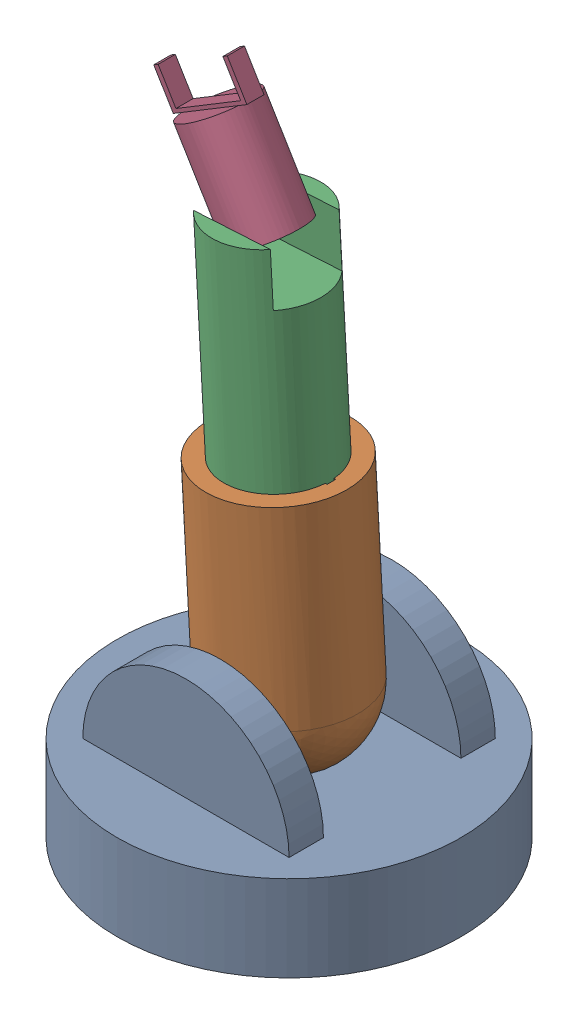
SolidWorks assembly Assem1, configuration Default. Lengths in mm.
Overall size (200 380.93 200).
4 component instances, 4 part files, 4 mates.
Components (placement in the parent):
- part1-1: part1 [Default] at (-37.4269 31.4025 224.8685) size (200 110 200)
- Part2-1: Part2 [Default] at (-37.4269 111.4025 224.8685) x (0.998352 0.057379 0) z (-0.057379 0.998352 0) size (80 100 150)
- Part3-1: Part3 [Default] at (-50.624 341.0236 224.8685) x (0 0 -1) z (0.057379 -0.998352 0) size (60 61 220)
- Part4-1: Part4 [Default] at (-48.3769 330.9431 224.8685) x (0.855727 0.517427 0) z (-0.517427 0.855727 0) size (50 50 80)
Mates (geometry in assembly coordinates):
- Coincident1: coincident anti-aligned: circle of part1-1; circle of Part2-1
- Coincident16: coincident anti-aligned: circle of Part2-1; circle of Part3-1
- Coincident17: coincident: line of Part2-1 through (-7.0518 123.1648 227.3685) axis (-0.057379 0.998352 0); moEndPointRef_w of Part3-1
- Coincident19: coincident anti-aligned: circle of Part3-1; circle of Part4-1
